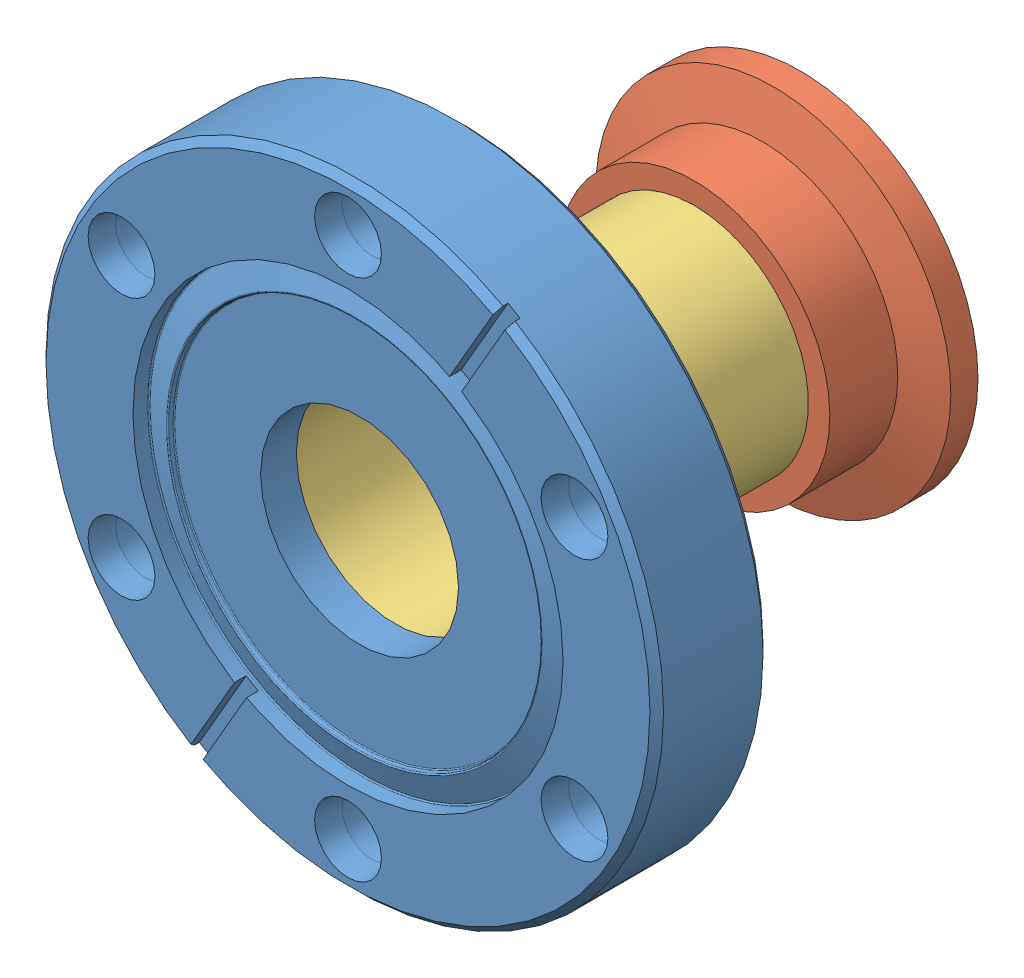
SolidWorks assembly 730002, configuration Default. Lengths in mm.
Overall size (69.34 69.34 50.8).
3 component instances, 3 part files, 4 mates.
Components (placement in the parent):
- 110012-1: 110012 [Default] at (25.6288 31.4857 50.2039) size (69.34 69.34 12.7)
- 713002-1: 713002 [Default] at (25.6288 31.4857 12.1039) x (0.858757 -0.512383 0) z (0 0 1) size (39.88 39.88 11.94)
- 940132-1: 940132 [Default] at (25.6288 31.4857 16.4219) x (0.944769 -0.327737 0) z (0 0 1) size (25.65 25.65 41.17)
Mates (geometry in assembly coordinates):
- Concentric1: concentric aligned: cylinder of 110012-1 through (25.6288 31.4857 50.2039) axis (0 0 -1) radius 12.827; cylinder of 940132-1 through (25.6288 31.4857 57.5953) axis (0 0 -1) radius 12.827
- Coincident1: coincident anti-aligned: plane of 110012-1 through (38.4558 31.4857 57.5953) normal (0 0 -1); plane of 940132-1 through (25.6288 31.4857 57.5953) normal (0 0 1)
- Concentric2: concentric aligned: cylinder of 713002-1 through (25.6288 31.4857 -26.802) axis (0 0 -1) radius 12.827; cylinder of 940132-1 through (25.6288 31.4857 57.5953) axis (0 0 -1) radius 12.827
- Coincident2: coincident anti-aligned: plane of 713002-1 through (25.6288 31.4857 16.4219) normal (0 0 1); plane of 940132-1 through (25.6288 31.4857 16.4219) normal (0 0 -1)
